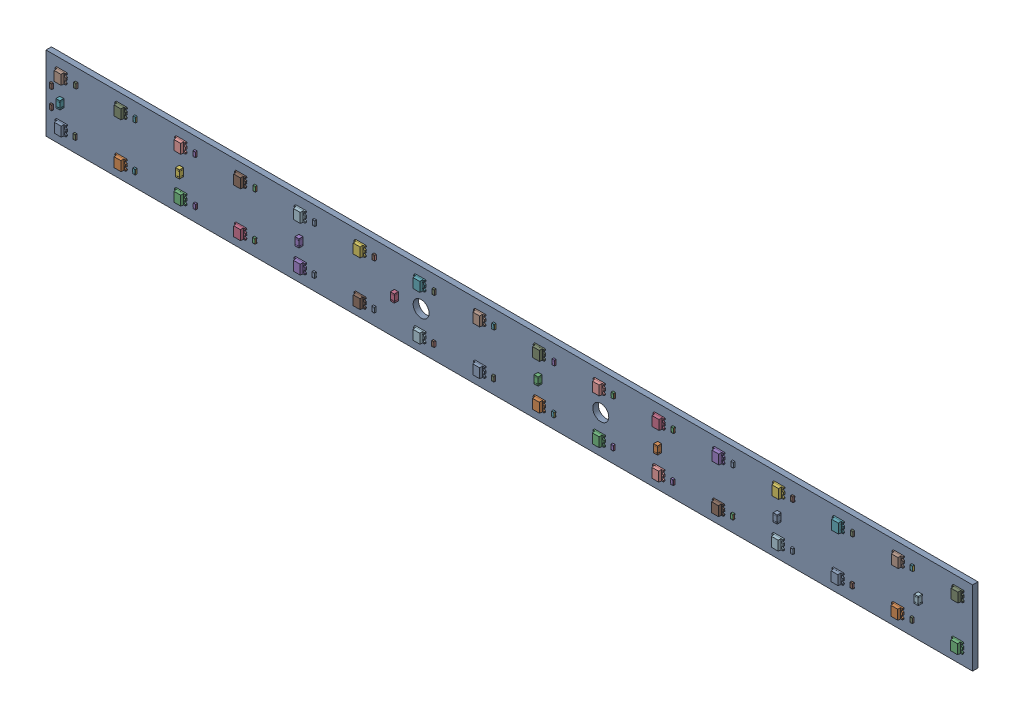
SolidWorks assembly Pedal_LoopLEDS, configuration Default. Lengths in mm.
Overall size (186 15 6.7).
154 component instances, 8 part files, 0 mates.
Components (placement in the parent):
- Board-1: Board [Default] at origin size (186 15 1.09)
  - Open CASCADE STEP translator 7.5 3.1.1-1: Open CASCADE STEP translator 7.5 3.1.1 [Default] at (0 0 -1.0914) size (186 15 1.09)
- J2-1: J2 [Default] at origin size (5.48 5.85 4.75)
  - 9705581488-1: 9705581488 [Default] at (208.451 98.62 -1.0914) x (1 0 0) z (0 0 -1) size (5.48 5.85 4.75)
    - Body-1: Body [Default] at (0 0 0.1) size (5.48 3.1 4.65)
    - Pins-1: Pins [Default] at origin size (4.42 5.85 0.1)
- J1-1: J1 [Default] at origin size (5.48 5.85 4.75)
  - 9452610336-1: 9452610336 [Default] at (39.751 98.484 -1.0914) x (-1 0 0) z (0 0 -1) size (5.48 5.85 4.75)
    - Body-0-1: Body-0 [Default] at (0 0 0.1) size (5.48 3.1 4.65)
    - Pins-1-1: Pins-1 [Default] at origin size (4.42 5.85 0.1)
- R32-1: R32 [Default] at origin size (0.5 1 0.35)
  - 0402 resistor-1: 0402 resistor [Default] at (205.2627 94.0499 0) x (0 -1 0) z (-1 0 0) size (1 0.35 0.5)
- R31-1: R31 [Default] at origin size (0.5 1 0.35)
  - 0402 resistor-1: 0402 resistor [Default] at (193.2627 94.0499 0) x (0 -1 0) z (-1 0 0) size (1 0.35 0.5)
- R30-1: R30 [Default] at origin size (0.5 1 0.35)
  - 0402 resistor-1: 0402 resistor [Default] at (181.2627 94.0499 0) x (0 -1 0) z (-1 0 0) size (1 0.35 0.5)
- R29-1: R29 [Default] at origin size (0.5 1 0.35)
  - 0402 resistor-1: 0402 resistor [Default] at (169.2627 94.0499 0) x (0 -1 0) z (-1 0 0) size (1 0.35 0.5)
- R28-1: R28 [Default] at origin size (0.5 1 0.35)
  - 0402 resistor-1: 0402 resistor [Default] at (157.2627 94.0499 0) x (0 -1 0) z (-1 0 0) size (1 0.35 0.5)
- R27-1: R27 [Default] at origin size (0.5 1 0.35)
  - 0402 resistor-1: 0402 resistor [Default] at (205.3175 103.12 0) x (0 -1 0) z (-1 0 0) size (1 0.35 0.5)
- R26-1: R26 [Default] at origin size (0.5 1 0.35)
  - 0402 resistor-1: 0402 resistor [Default] at (193.3175 103.12 0) x (0 -1 0) z (-1 0 0) size (1 0.35 0.5)
- R25-1: R25 [Default] at origin size (0.5 1 0.35)
  - 0402 resistor-1: 0402 resistor [Default] at (181.3175 103.12 0) x (0 -1 0) z (-1 0 0) size (1 0.35 0.5)
- R24-1: R24 [Default] at origin size (0.5 1 0.35)
  - 0402 resistor-1: 0402 resistor [Default] at (169.3175 103.12 0) x (0 -1 0) z (-1 0 0) size (1 0.35 0.5)
- R23-1: R23 [Default] at origin size (0.5 1 0.35)
  - 0402 resistor-1: 0402 resistor [Default] at (157.3175 103.12 0) x (0 -1 0) z (-1 0 0) size (1 0.35 0.5)
- R22-1: R22 [Default] at origin size (0.5 1 0.35)
  - 0402 resistor-1: 0402 resistor [Default] at (145.2627 94.0499 0) x (0 -1 0) z (-1 0 0) size (1 0.35 0.5)
- R21-1: R21 [Default] at origin size (0.5 1 0.35)
  - 0402 resistor-1: 0402 resistor [Default] at (133.3477 93.8532 0) x (0 -1 0) z (-1 0 0) size (1 0.35 0.5)
- R20-1: R20 [Default] at origin size (0.5 1 0.35)
  - 0402 resistor-1: 0402 resistor [Default] at (121.2627 94.0499 0) x (0 -1 0) z (-1 0 0) size (1 0.35 0.5)
- R19-1: R19 [Default] at origin size (0.5 1 0.35)
  - 0402 resistor-1: 0402 resistor [Default] at (109.2627 94.0499 0) x (0 -1 0) z (-1 0 0) size (1 0.35 0.5)
- R18-1: R18 [Default] at origin size (0.5 1 0.35)
  - 0402 resistor-1: 0402 resistor [Default] at (97.2627 94.0499 0) x (0 -1 0) z (-1 0 0) size (1 0.35 0.5)
- R17-1: R17 [Default] at origin size (0.5 1 0.35)
  - 0402 resistor-1: 0402 resistor [Default] at (145.3175 103.12 0) x (0 -1 0) z (-1 0 0) size (1 0.35 0.5)
- R16-1: R16 [Default] at origin size (0.5 1 0.35)
  - 0402 resistor-1: 0402 resistor [Default] at (133.4025 102.9234 0) x (0 -1 0) z (-1 0 0) size (1 0.35 0.5)
- R15-1: R15 [Default] at origin size (0.5 1 0.35)
  - 0402 resistor-1: 0402 resistor [Default] at (121.3175 103.12 0) x (0 -1 0) z (-1 0 0) size (1 0.35 0.5)
- R14-1: R14 [Default] at origin size (0.5 1 0.35)
  - 0402 resistor-1: 0402 resistor [Default] at (109.3175 103.12 0) x (0 -1 0) z (-1 0 0) size (1 0.35 0.5)
- R13-1: R13 [Default] at origin size (0.5 1 0.35)
  - 0402 resistor-1: 0402 resistor [Default] at (97.3175 103.12 0) x (0 -1 0) z (-1 0 0) size (1 0.35 0.5)
- R12-1: R12 [Default] at origin size (0.5 1 0.35)
  - 0402 resistor-1: 0402 resistor [Default] at (85.2627 94.0499 0) x (0 -1 0) z (-1 0 0) size (1 0.35 0.5)
- R11-1: R11 [Default] at origin size (0.5 1 0.35)
  - 0402 resistor-1: 0402 resistor [Default] at (73.3064 94.0407 0) x (0 -1 0) z (-1 0 0) size (1 0.35 0.5)
- R10-1: R10 [Default] at origin size (0.5 1 0.35)
  - 0402 resistor-1: 0402 resistor [Default] at (61.4068 94.0487 0) x (0 -1 0) z (-1 0 0) size (1 0.35 0.5)
- R9-1: R9 [Default] at origin size (0.5 1 0.35)
  - 0402 resistor-1: 0402 resistor [Default] at (49.2627 94.0499 0) x (0 -1 0) z (-1 0 0) size (1 0.35 0.5)
- R8-1: R8 [Default] at origin size (0.5 1 0.35)
  - 0402 resistor-1: 0402 resistor [Default] at (37.2627 94.0499 0) x (0 -1 0) z (-1 0 0) size (1 0.35 0.5)
- R7-1: R7 [Default] at origin size (0.5 1 0.35)
  - 0402 resistor-1: 0402 resistor [Default] at (32.008 96.8409 0) x (0 1 0) z (1 0 0) size (1 0.35 0.5)
- R6-1: R6 [Default] at origin size (0.5 1 0.35)
  - 0402 resistor-1: 0402 resistor [Default] at (85.3175 103.12 0) x (0 -1 0) z (-1 0 0) size (1 0.35 0.5)
- R5-1: R5 [Default] at origin size (0.5 1 0.35)
  - 0402 resistor-1: 0402 resistor [Default] at (73.3613 103.1109 0) x (0 -1 0) z (-1 0 0) size (1 0.35 0.5)
- R4-1: R4 [Default] at origin size (0.5 1 0.35)
  - 0402 resistor-1: 0402 resistor [Default] at (61.3613 103.1109 0) x (0 -1 0) z (-1 0 0) size (1 0.35 0.5)
- R3-1: R3 [Default] at origin size (0.5 1 0.35)
  - 0402 resistor-1: 0402 resistor [Default] at (49.3175 103.12 0) x (0 -1 0) z (-1 0 0) size (1 0.35 0.5)
- R2-1: R2 [Default] at origin size (0.5 1 0.35)
  - 0402 resistor-1: 0402 resistor [Default] at (37.3947 103.0429 0) x (0 -1 0) z (-1 0 0) size (1 0.35 0.5)
- R1-1: R1 [Default] at origin size (0.5 1 0.35)
  - 0402 resistor-1: 0402 resistor [Default] at (32.5079 100.5171 0) x (0 -1 0) z (-1 0 0) size (1 0.35 0.5)
- C9-1: C9 [Default] at origin size (0.82 1.6 0.82)
  - 0603 cap-1: 0603 cap [Default] at (206.5019 98.5521 0) x (0 1 0) z (1 0 0) size (1.6 0.82 0.82)
- C8-1: C8 [Default] at origin size (0.82 1.6 0.82)
  - 0603 cap-1: 0603 cap [Default] at (178.1883 98.5521 0) x (0 1 0) z (1 0 0) size (1.6 0.82 0.82)
- C7-1: C7 [Default] at origin size (0.82 1.6 0.82)
  - 0603 cap-1: 0603 cap [Default] at (154.1779 98.5521 0) x (0 1 0) z (1 0 0) size (1.6 0.82 0.82)
- C6-1: C6 [Default] at origin size (0.82 1.6 0.82)
  - 0603 cap-1: 0603 cap [Default] at (130.1883 98.5521 0) x (0 1 0) z (1 0 0) size (1.6 0.82 0.82)
- C5-1: C5 [Default] at origin size (0.82 1.6 0.82)
  - 0603 cap-1: 0603 cap [Default] at (101.3459 98.5521 0) x (0 1 0) z (1 0 0) size (1.6 0.82 0.82)
- C4-1: C4 [Default] at origin size (0.82 1.6 0.82)
  - 0603 cap-1: 0603 cap [Default] at (82.1883 98.5521 0) x (0 1 0) z (1 0 0) size (1.6 0.82 0.82)
- C3-1: C3 [Default] at origin size (0.82 1.6 0.82)
  - 0603 cap-1: 0603 cap [Default] at (58.1883 98.5521 0) x (0 1 0) z (1 0 0) size (1.6 0.82 0.82)
- C2-1: C2 [Default] at origin size (0.82 1.6 0.82)
  - 0603 cap-1: 0603 cap [Default] at (34.1883 98.5521 0) x (0 1 0) z (1 0 0) size (1.6 0.82 0.82)
- LED1-1: LED1 [Default] at origin size (2.2 2 0.86)
  - WS2812-2020-1: WS2812-2020 [Default] at (34.1903 103.1634 0.3) x (-1 0 0) z (0 1 0) size (2.2 0.86 2)
- LED2-1: LED2 [Default] at origin size (2.2 2 0.86)
  - WS2812-2020-1: WS2812-2020 [Default] at (46.2138 103.1748 0.3) x (-1 0 0) z (0 1 0) size (2.2 0.86 2)
- LED3-1: LED3 [Default] at origin size (2.2 2 0.86)
  - WS2812-2020-1: WS2812-2020 [Default] at (58.2138 103.1748 0.3) x (-1 0 0) z (0 1 0) size (2.2 0.86 2)
- LED4-1: LED4 [Default] at origin size (2.2 2 0.86)
  - WS2812-2020-1: WS2812-2020 [Default] at (70.2138 103.1748 0.3) x (-1 0 0) z (0 1 0) size (2.2 0.86 2)
- LED5-1: LED5 [Default] at origin size (2.2 2 0.86)
  - WS2812-2020-1: WS2812-2020 [Default] at (82.2138 103.1748 0.3) x (-1 0 0) z (0 1 0) size (2.2 0.86 2)
- LED6-1: LED6 [Default] at origin size (2.2 2 0.86)
  - WS2812-2020-1: WS2812-2020 [Default] at (34.2138 94.1748 0.3) x (-1 0 0) z (0 1 0) size (2.2 0.86 2)
- LED7-1: LED7 [Default] at origin size (2.2 2 0.86)
  - WS2812-2020-1: WS2812-2020 [Default] at (46.2138 94.1748 0.3) x (-1 0 0) z (0 1 0) size (2.2 0.86 2)
- LED8-1: LED8 [Default] at origin size (2.2 2 0.86)
  - WS2812-2020-1: WS2812-2020 [Default] at (58.2138 94.1748 0.3) x (-1 0 0) z (0 1 0) size (2.2 0.86 2)
- LED9-1: LED9 [Default] at origin size (2.2 2 0.86)
  - WS2812-2020-1: WS2812-2020 [Default] at (70.2138 94.1748 0.3) x (-1 0 0) z (0 1 0) size (2.2 0.86 2)
- LED10-1: LED10 [Default] at origin size (2.2 2 0.86)
  - WS2812-2020-1: WS2812-2020 [Default] at (82.2138 94.1748 0.3) x (-1 0 0) z (0 1 0) size (2.2 0.86 2)
- LED11-1: LED11 [Default] at origin size (2.2 2 0.86)
  - WS2812-2020-1: WS2812-2020 [Default] at (94.2138 103.1748 0.3) x (-1 0 0) z (0 1 0) size (2.2 0.86 2)
- LED12-1: LED12 [Default] at origin size (2.2 2 0.86)
  - WS2812-2020-1: WS2812-2020 [Default] at (106.2138 103.1748 0.3) x (-1 0 0) z (0 1 0) size (2.2 0.86 2)
- LED13-1: LED13 [Default] at origin size (2.2 2 0.86)
  - WS2812-2020-1: WS2812-2020 [Default] at (118.2138 103.1748 0.3) x (-1 0 0) z (0 1 0) size (2.2 0.86 2)
- LED14-1: LED14 [Default] at origin size (2.2 2 0.86)
  - WS2812-2020-1: WS2812-2020 [Default] at (130.2138 103.1748 0.3) x (-1 0 0) z (0 1 0) size (2.2 0.86 2)
- LED15-1: LED15 [Default] at origin size (2.2 2 0.86)
  - WS2812-2020-1: WS2812-2020 [Default] at (142.2138 103.1748 0.3) x (-1 0 0) z (0 1 0) size (2.2 0.86 2)
- LED16-1: LED16 [Default] at origin size (2.2 2 0.86)
  - WS2812-2020-1: WS2812-2020 [Default] at (94.2138 94.1748 0.3) x (-1 0 0) z (0 1 0) size (2.2 0.86 2)
- LED17-1: LED17 [Default] at origin size (2.2 2 0.86)
  - WS2812-2020-1: WS2812-2020 [Default] at (106.2138 94.1748 0.3) x (-1 0 0) z (0 1 0) size (2.2 0.86 2)
- LED18-1: LED18 [Default] at origin size (2.2 2 0.86)
  - WS2812-2020-1: WS2812-2020 [Default] at (118.2138 94.1748 0.3) x (-1 0 0) z (0 1 0) size (2.2 0.86 2)
- LED19-1: LED19 [Default] at origin size (2.2 2 0.86)
  - WS2812-2020-1: WS2812-2020 [Default] at (130.2138 94.1748 0.3) x (-1 0 0) z (0 1 0) size (2.2 0.86 2)
- LED20-1: LED20 [Default] at origin size (2.2 2 0.86)
  - WS2812-2020-1: WS2812-2020 [Default] at (142.2138 94.1748 0.3) x (-1 0 0) z (0 1 0) size (2.2 0.86 2)
- LED21-1: LED21 [Default] at origin size (2.2 2 0.86)
  - WS2812-2020-1: WS2812-2020 [Default] at (154.2286 103.1782 0.3) x (-1 0 0) z (0 1 0) size (2.2 0.86 2)
- LED22-1: LED22 [Default] at origin size (2.2 2 0.86)
  - WS2812-2020-1: WS2812-2020 [Default] at (166.2286 103.1782 0.3) x (-1 0 0) z (0 1 0) size (2.2 0.86 2)
- LED23-1: LED23 [Default] at origin size (2.2 2 0.86)
  - WS2812-2020-1: WS2812-2020 [Default] at (178.2286 103.1782 0.3) x (-1 0 0) z (0 1 0) size (2.2 0.86 2)
- LED24-1: LED24 [Default] at origin size (2.2 2 0.86)
  - WS2812-2020-1: WS2812-2020 [Default] at (190.2286 103.1782 0.3) x (-1 0 0) z (0 1 0) size (2.2 0.86 2)
- LED25-1: LED25 [Default] at origin size (2.2 2 0.86)
  - WS2812-2020-1: WS2812-2020 [Default] at (202.2286 103.1782 0.3) x (-1 0 0) z (0 1 0) size (2.2 0.86 2)
- LED26-1: LED26 [Default] at origin size (2.2 2 0.86)
  - WS2812-2020-1: WS2812-2020 [Default] at (214.2286 103.1782 0.3) x (-1 0 0) z (0 1 0) size (2.2 0.86 2)
- LED27-1: LED27 [Default] at origin size (2.2 2 0.86)
  - WS2812-2020-1: WS2812-2020 [Default] at (154.1571 94.166 0.3) x (-1 0 0) z (0 1 0) size (2.2 0.86 2)
- LED28-1: LED28 [Default] at origin size (2.2 2 0.86)
  - WS2812-2020-1: WS2812-2020 [Default] at (166.1571 94.166 0.3) x (-1 0 0) z (0 1 0) size (2.2 0.86 2)
- LED29-1: LED29 [Default] at origin size (2.2 2 0.86)
  - WS2812-2020-1: WS2812-2020 [Default] at (178.1571 94.166 0.3) x (-1 0 0) z (0 1 0) size (2.2 0.86 2)
- LED30-1: LED30 [Default] at origin size (2.2 2 0.86)
  - WS2812-2020-1: WS2812-2020 [Default] at (190.1571 94.166 0.3) x (-1 0 0) z (0 1 0) size (2.2 0.86 2)
- LED31-1: LED31 [Default] at origin size (2.2 2 0.86)
  - WS2812-2020-1: WS2812-2020 [Default] at (202.1571 94.166 0.3) x (-1 0 0) z (0 1 0) size (2.2 0.86 2)
- LED32-1: LED32 [Default] at origin size (2.2 2 0.86)
  - WS2812-2020-1: WS2812-2020 [Default] at (214.1571 94.166 0.3) x (-1 0 0) z (0 1 0) size (2.2 0.86 2)
